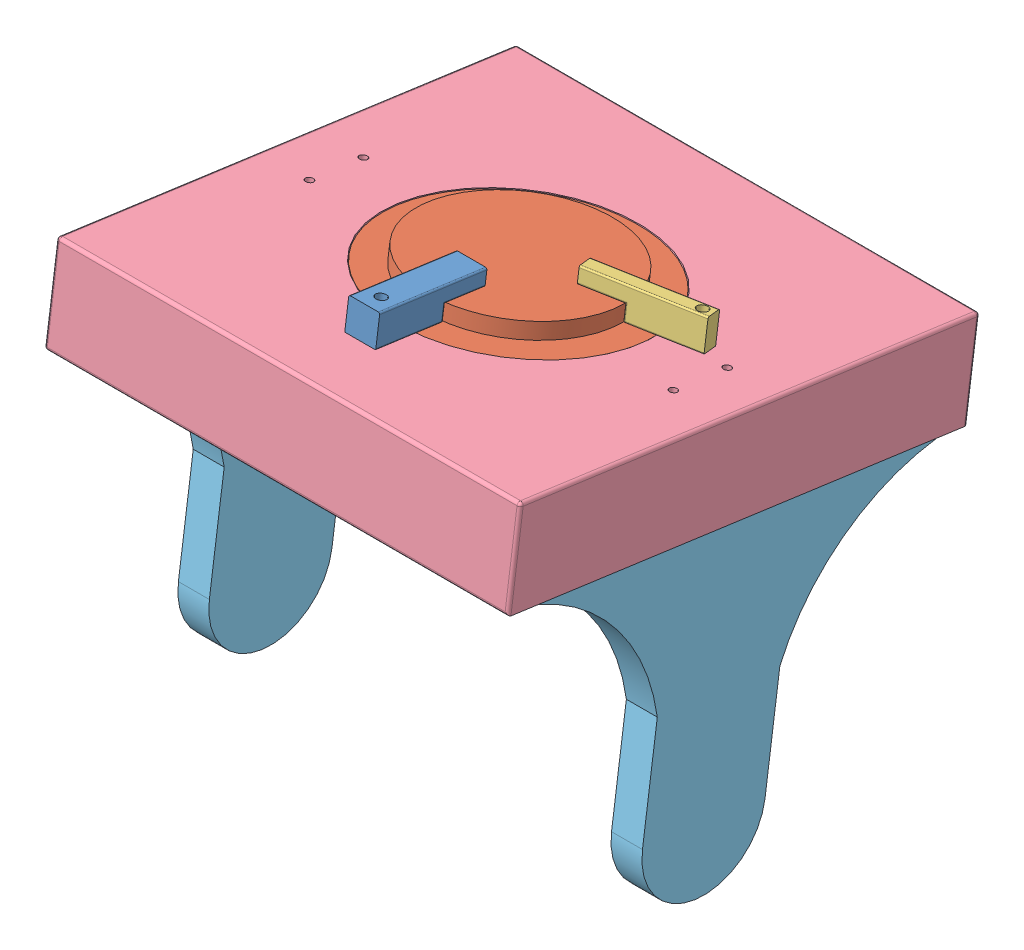
SolidWorks assembly Shaker_v2_copyjoin, configuration Default. Lengths in mm.
Overall size (150 154.54 156.49).
6 component instances, 5 part files, 12 mates.
Components (placement in the parent):
- Clamp_Shaker_v2-1: Clamp_Shaker_v2 [Default] at (-457.1906 -36.8871 -10.1136) x (0 -0.13704 -0.990565) z (0 0.990565 -0.13704) size (35 10 10)
- Outline for Chamber-1: Outline for Chamber [Default] at (-457.5759 -41.615 -44.2881) x (-0.999474 0.004443 0.032119) z (0.032425 0.136968 0.990045) size (78 15 78)
- Small_Clamp-2: Small_Clamp [Default] at (-423.8878 -37.6818 -52.3437) x (0.976467 -0.029555 -0.213633) z (0 -0.990565 0.13704) size (35 5 10)
- Platform_Shaker_COPYNEW-1: Platform_Shaker_COPYNEW [Default] at (-457.5759 -46.3949 -43.6269) x (-1 0 0) z (0 0.990565 -0.13704) size (150 150 30)
- Bracket for Platform-3: Bracket for Platform [Default] at (-392.5759 -147.1132 -9.5024) x (0 -0.13704 -0.990565) z (1 0 0) size (130 100 30)
- Bracket for Platform-6: Bracket for Platform [Default] at (-522.5759 -152.5948 -49.1251) x (0 0.13704 0.990565) z (-1 0 0) size (130 100 30)
Mates (geometry in assembly coordinates):
- Coincident5: coincident anti-aligned: plane of Clamp_Shaker_v2-1 through (-457.1906 -36.8871 -10.1136) normal (0 -0.990565 0.13704); plane of Outline for Chamber-1 through (-457.5759 -41.615 -44.2881) normal (0 0.990565 -0.13704)
- Tangent4: tangent anti-aligned: cylinder of Outline for Chamber-1 through (-457.5759 -46.5678 -43.6029) axis (0 0.990565 -0.13704) radius 30; plane of Small_Clamp-2 through (-427.7428 -47.1199 -47.5938) normal (-0.976467 0.029555 0.213633)
- Concentric6: concentric aligned: cylinder of Outline for Chamber-1 through (-457.5759 -56.4735 -42.2325) axis (0 0.990565 -0.13704) radius 39; cylinder of Platform_Shaker_COPYNEW-1 through (-457.5759 -56.3006 -42.2565) axis (0 0.990565 -0.13704) radius 39.25
- Parallel3: parallel aligned: plane of Clamp_Shaker_v2-1 through (-462.1906 -29.5361 6.5361) normal (-1 0 0); plane of Platform_Shaker_COPYNEW-1 through (-532.5759 -86.3899 -113.8081) normal (-1 0 0)
- Parallel4: parallel aligned: plane of Clamp_Shaker_v2-1 through (-452.1906 -29.5361 6.5361) normal (0 0.13704 0.990565); plane of Platform_Shaker_COPYNEW-1 through (-382.5759 -65.8338 34.7768) normal (0 0.13704 0.990565)
- Coincident32: coincident anti-aligned: plane of Platform_Shaker_COPYNEW-1 through (-457.5759 -76.1119 -39.5157) normal (0 -0.990565 0.13704); plane of Bracket for Platform-3 through (-382.5759 -73.3711 -19.7043) normal (0 0.990565 -0.13704)
- Coincident33: coincident aligned: line of Platform_Shaker_COPYNEW-1 through (-382.5759 -86.2529 -112.8175) axis (0 0.13704 0.990565); line of Bracket for Platform-3 through (-382.5759 -85.0195 -103.9024) axis (0 0.13704 0.990565)
- Coincident40: coincident: point of Platform_Shaker_COPYNEW-1; unknown of Bracket for Platform-3
- Coincident41: coincident anti-aligned: plane of Platform_Shaker_COPYNEW-1 through (-457.5759 -76.1119 -39.5157) normal (0 -0.990565 0.13704); plane of Bracket for Platform-5 through (-531.5759 -78.4007 -54.786) normal (0 0.990565 -0.13704)
- Coincident42: coincident aligned: line of Platform_Shaker_COPYNEW-1 through (-531.5759 -65.9709 33.7862) axis (0 -0.13704 -0.990565); line of Bracket for Platform-5 through (-531.5759 -66.7522 29.4121) axis (0 -0.13704 -0.990565)
- Coincident43: coincident anti-aligned: plane of Platform_Shaker_COPYNEW-1 through (-457.5759 -76.1119 -39.5157) normal (0 -0.990565 0.13704); plane of Bracket for Platform-6 through (-532.5759 -78.8527 -59.327) normal (0 0.990565 -0.13704)
- Coincident53: coincident: unknown of Platform_Shaker_COPYNEW-1; moEndPointRef_w of Bracket for Platform-6
